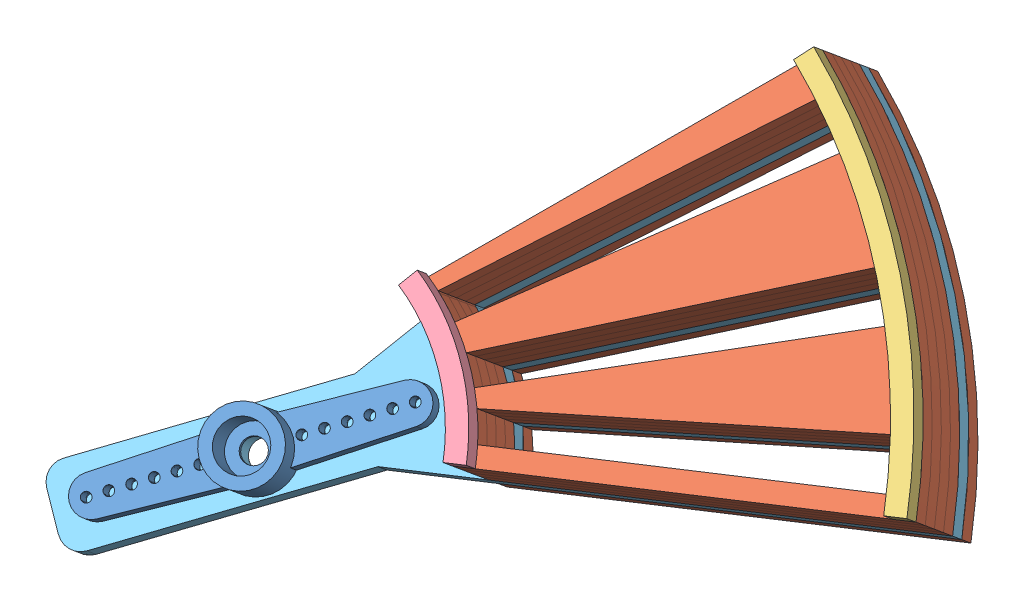
SolidWorks assembly coin assembly, configuration Default. Lengths in mm.
Overall size (86.45 52.05 68.59).
9 component instances, 5 part files, 25 mates.
Components (placement in the parent):
- Microservo horn-1: Microservo horn [По умолчанию] at (-5.665 -42.9874 8.9754) x (0.678115 0.347417 -0.647658) z (0.338464 0.634594 0.69479) size (32 7.5 5)
- Part1Middle-1: Part1Middle [Default] at (-1.6034 -35.3722 17.3129) x (-0.888605 -0.027346 0.457857) z (-0.338464 -0.634594 -0.69479) size (46.36 38.84 3)
- Part3Bottom-1: Part3Bottom [Default] at (-0.588 -33.4685 19.3973) x (-0.940974 0.230714 0.247667) z (-0.338464 -0.634594 -0.69479) size (27.41 30.99 3)
- Part4Bottom-1: Part4Bottom [Default] at (-1.6034 -35.3722 17.3129) x (0.262908 -0.772739 0.577715) z (0.338464 0.634594 0.69479) size (15.09 9.1 3)
- Part9Top-1: Part9Top [Default] at (-5.665 -42.9874 8.9754) x (-0.888605 -0.027346 0.457857) z (-0.338464 -0.634594 -0.69479) size (77.33 50.1 3)
- Part1Middle-2: Part1Middle [Default] at (-2.6188 -37.276 15.2285) x (-0.888605 -0.027346 0.457857) z (-0.338464 -0.634594 -0.69479) size (46.36 38.84 3)
- Part1Middle-3: Part1Middle [Default] at (-3.6342 -39.1798 13.1442) x (-0.888605 -0.027346 0.457857) z (-0.338464 -0.634594 -0.69479) size (46.36 38.84 3)
- Part1Middle-4: Part1Middle [Default] at (-4.6496 -41.0836 11.0598) x (-0.888605 -0.027346 0.457857) z (-0.338464 -0.634594 -0.69479) size (46.36 38.84 3)
- Part1Middle-5: Part1Middle [Default] at (-6.6804 -44.8912 6.891) x (-0.888605 -0.027346 0.457857) z (-0.338464 -0.634594 -0.69479) size (46.36 38.84 3)
Mates (geometry in assembly coordinates):
- Coincident1: coincident: plane of Part1Middle-1 through (-1.6034 -35.3722 17.3129) normal (0.338464 0.634594 0.69479); plane of Part3Bottom-1 through (-1.6034 -35.3722 17.3129) normal (-0.338464 -0.634594 -0.69479)
- Coincident2: coincident: circle of Part1Middle-1; circle of Part3Bottom-1
- Coincident3: coincident: point of Part1Middle-1; point of Part3Bottom-1
- Coincident4: coincident: plane of Part1Middle-1 through (-1.6034 -35.3722 17.3129) normal (0.338464 0.634594 0.69479); plane of Part4Bottom-1 through (-1.6034 -35.3722 17.3129) normal (-0.338464 -0.634594 -0.69479)
- Coincident5: coincident: circle of Part1Middle-1; circle of Part4Bottom-1
- Coincident6: coincident: point of Part1Middle-1; point of Part4Bottom-1
- Coincident7: coincident: plane of Part1Middle-1 through (-2.6188 -37.276 15.2285) normal (-0.338464 -0.634594 -0.69479); plane of Part1Middle-2 through (-2.6188 -37.276 15.2285) normal (0.338464 0.634594 0.69479)
- Coincident8: coincident: line of Part1Middle-1 through (14.9042 -36.1404 5.655) axis (0.876152 0.056784 -0.478678); line of Part1Middle-2 through (14.9042 -36.1404 5.655) axis (0.876152 0.056784 -0.478678)
- Coincident9: coincident: point of Part1Middle-1; point of Part1Middle-2
- Coincident10: coincident: plane of Part1Middle-2 through (-3.6342 -39.1798 13.1442) normal (-0.338464 -0.634594 -0.69479); plane of Part1Middle-3 through (-3.6342 -39.1798 13.1442) normal (0.338464 0.634594 0.69479)
- Coincident11: coincident: plane of Part1Middle-2 through (13.8889 -38.0441 3.5706) normal (0.343219 -0.770757 0.536781); plane of Part1Middle-3 through (12.8735 -39.9479 1.4862) normal (0.343219 -0.770757 0.536781)
- Coincident12: coincident: point of Part1Middle-2; point of Part1Middle-3
- Coincident13: coincident: plane of Part1Middle-3 through (-4.6496 -41.0836 11.0598) normal (-0.338464 -0.634594 -0.69479); plane of Part1Middle-4 through (-4.6496 -41.0836 11.0598) normal (0.338464 0.634594 0.69479)
- Coincident14: coincident: plane of Part1Middle-3 through (12.8735 -39.9479 1.4862) normal (0.343219 -0.770757 0.536781); plane of Part1Middle-4 through (11.8581 -41.8517 -0.5982) normal (0.343219 -0.770757 0.536781)
- Coincident15: coincident: point of Part1Middle-3; point of Part1Middle-4
- Coincident16: coincident: plane of Part9Top-1 through (-5.665 -42.9874 8.9754) normal (0.338464 0.634594 0.69479); plane of Part1Middle-4 through (-5.665 -42.9874 8.9754) normal (-0.338464 -0.634594 -0.69479)
- Coincident17: coincident: line of Part9Top-1 through (3.493 -42.3938 3.972) axis (0.876152 0.056784 -0.478678); line of Part1Middle-4 through (11.8581 -41.8517 -0.5982) axis (0.876152 0.056784 -0.478678)
- Coincident18: coincident: point of Part9Top-1; point of Part1Middle-4
- Coincident24: coincident: plane of Part9Top-1 through (-6.6804 -44.8912 6.891) normal (-0.338464 -0.634594 -0.69479); plane of Part1Middle-5 through (-6.6804 -44.8912 6.891) normal (0.338464 0.634594 0.69479)
- Coincident25: coincident: line of Part9Top-1 through (2.4776 -44.2976 1.8877) axis (0.876152 0.056784 -0.478678); line of Part1Middle-5 through (10.8427 -43.7555 -2.6825) axis (0.876152 0.056784 -0.478678)
- Coincident26: coincident: point of Part9Top-1; point of Part1Middle-5
- Concentric3: concentric: cylinder of Microservo horn-1 through (-5.665 -42.9874 8.9754) axis (0.338464 0.634594 0.69479) radius 2.5; cylinder of Part9Top-1 through (-6.6804 -44.8912 6.891) axis (0.338464 0.634594 0.69479) radius 1.5
- Concentric5: concentric: cylinder of Microservo horn-1 through (-5.665 -42.9874 8.9754) axis (0.338464 0.634594 0.69479) radius 2.5; cylinder of Part9Top-1 through (-6.6804 -44.8912 6.891) axis (0.338464 0.634594 0.69479) radius 1.5
- Distance3: distance = 4 mm: cylinder of Microservo horn-1 through (-1.9365 -40.1548 7.4505) axis (-0.338464 -0.634594 -0.69479) radius 0.5; line of Part9Top-1 through (-1.726 -36.871 1.4701) axis (-0.678115 -0.347417 0.647658)
- Coincident29: coincident: plane of Microservo horn-1 through (-5.665 -42.9874 8.9754) normal (-0.338464 -0.634594 -0.69479); plane of Part9Top-1 through (-5.665 -42.9874 8.9754) normal (0.338464 0.634594 0.69479)
